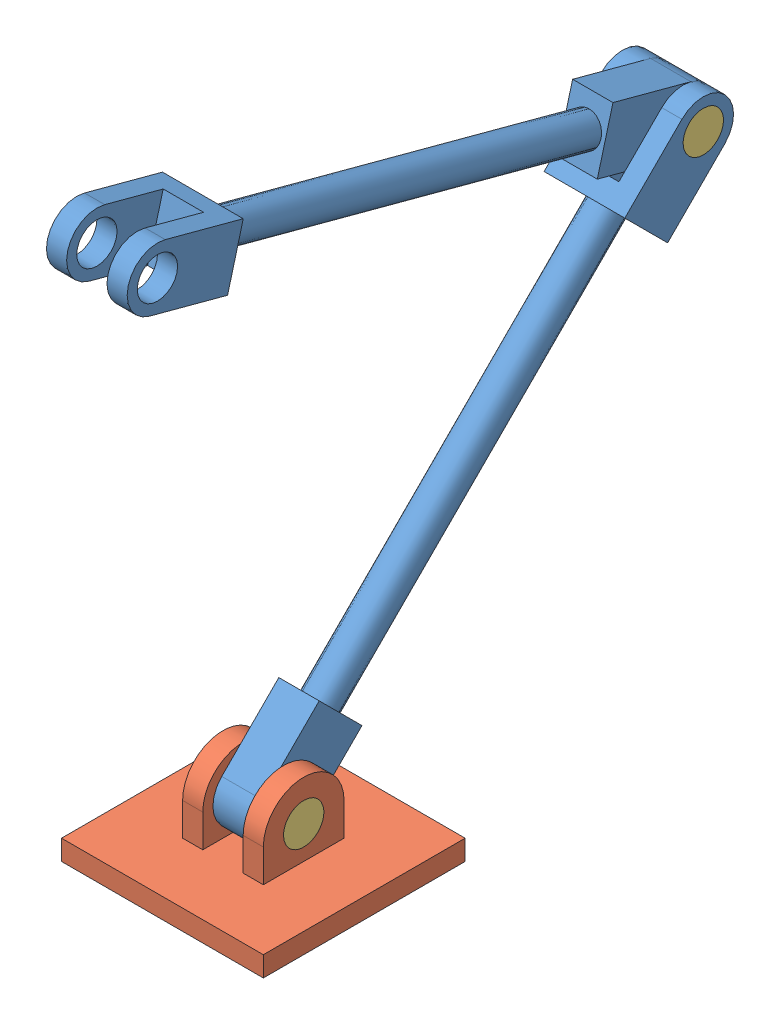
SolidWorks assembly CSOM01_SmithF, configuration Default. Lengths in mm.
Overall size (50 157.51 155.02).
5 component instances, 3 part files, 11 mates.
Components (placement in the parent):
- ARM-1: ARM [Default] at (0 62.5952 -74.4975) x (1 0 0) z (0 0.707107 0.707107) size (20 155 15)
- Base-1: Base [Default] at origin size (50 23.1 50)
- Pin-1: Pin [Default] at (0 13.0977 -25) x (0 0.365246 -0.930911) z (1 0 0) size (10 10 20)
- ARM-2: ARM [Default] at (0 130.21 -56.3801) x (1 0 0) z (0 -0.965926 0.258819) size (20 155 15)
- Pin-2: Pin [Default] at (0 112.0926 -123.9949) x (0 -0.45261 -0.891709) z (-1 0 0) size (10 10 20)
Mates (geometry in assembly coordinates):
- Coincident1: coordinate: point of assembly; point of Base-1; point of assembly
- Coincident2: coincident: plane of ARM-1 through (5 13.0977 -25) normal (1 0 0); plane of Base-1 through (5 13.0977 -25) normal (-1 0 0)
- Concentric1: concentric: cylinder of ARM-1 through (-15 13.0977 -25) axis (1 0 0) radius 5; cylinder of Base-1 through (-25 13.0977 -25) axis (1 0 0) radius 5
- Concentric2: concentric: cylinder of ARM-1 through (-15 13.0977 -25) axis (1 0 0) radius 5; cylinder of Pin-1 through (10 13.0977 -25) axis (-1 0 0) radius 5
- Coincident3: coincident: plane of Base-1 through (-10 13.0977 -25) normal (-1 0 0); plane of Pin-1 through (-10 13.0977 -25) normal (-1 0 0)
- Coincident5: coincident: plane of ARM-1 through (5 -80.5939 -108.085) normal (-1 0 0); plane of ARM-2 through (5 -85.8972 -123.9949) normal (1 0 0)
- Concentric4: concentric: cylinder of ARM-1 through (-10 -85.8972 -123.9949) axis (1 0 0) radius 5; cylinder of ARM-2 through (-15 -85.8972 -123.9949) axis (1 0 0) radius 5
- Concentric5: concentric: cylinder of ARM-2 through (-15 -85.8972 -123.9949) axis (1 0 0) radius 5; cylinder of Pin-2 through (-10 -85.8972 -123.9949) axis (1 0 0) radius 5
- Coincident6: coincident: plane of ARM-1 through (-10 -85.8972 -123.9949) normal (-1 0 0); plane of Pin-2 through (-10 -85.8972 -123.9949) normal (-1 0 0)
- Angle2: planar angle = 1.047198 rad: plane of ARM-2 through (5 110.0246 -102.7353) normal (0 -0.965926 0.258819); plane of ARM-1 through (10 103.2538 -104.5495) normal (0 0.707107 0.707107)
- Angle3: planar angle = 0.785398 rad: plane of ARM-1 through (5 21.9365 -44.4454) normal (0 -0.707107 -0.707107); plane of Base-1 through (-25 5 -50) normal (0 1 0)
